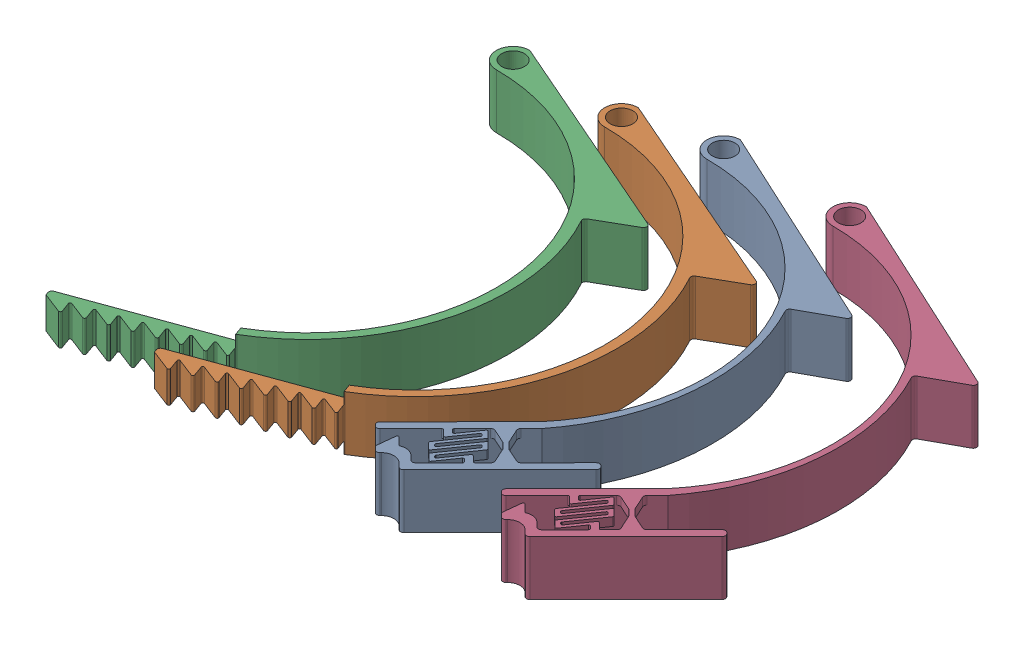
SolidWorks assembly ArmBandforPrinting v3, configuration Default. Lengths in mm.
Overall size (133.76 13 115.13).
4 component instances, 2 part files, 3 mates.
Components (placement in the parent):
- Arm Clamp v3.1-1: Arm Clamp v3.1 [Default] at (-24.1915 6.5795 8.2955) size (55.12 13 108.47)
- Arm Clamp inner v3.2-1: Arm Clamp inner v3.2 [Default] at (-43.0146 6.5795 13.8257) size (60.61 13 107.28)
- Arm Clamp inner v3.2-2: Arm Clamp inner v3.2 [Default] at (-67.7485 6.5795 14.9374) size (60.61 13 107.28)
- Arm Clamp v3.1-2: Arm Clamp v3.1 [Default] at (4.6423 6.5795 7.0902) size (55.12 13 108.47)
Mates (geometry in assembly coordinates):
- Coincident1: coincident aligned: plane of Arm Clamp v3.1-1 through (-24.1915 6.5795 8.2955) normal (0 -1 0); plane of Arm Clamp v3.1-2 through (4.6423 6.5795 7.0902) normal (0 -1 0)
- Coincident2: coincident aligned: plane of Arm Clamp v3.1-1 through (-24.1915 6.5795 8.2955) normal (0 -1 0); plane of Arm Clamp inner v3.2-1 through (-43.0146 6.5795 13.8257) normal (0 -1 0)
- Coincident3: coincident aligned: plane of Arm Clamp v3.1-1 through (-24.1915 6.5795 8.2955) normal (0 -1 0); plane of Arm Clamp inner v3.2-2 through (-67.7485 6.5795 14.9374) normal (0 -1 0)
